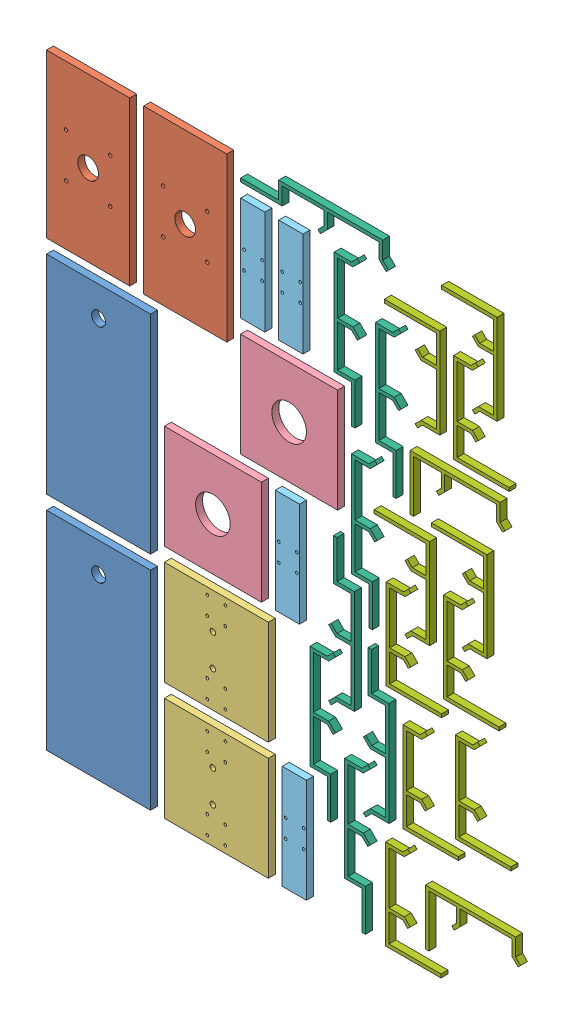
SolidWorks assembly Assem6, configuration Layout1[Steel_10mm_Qnty1]. Lengths in mm.
Overall size (1800 900 10).
32 component instances, 7 part files, 0 mates.
Components (placement in the parent):
- Z_Top_Plate-1: Z_Top_Plate [Default] at (85 160 0) x (1 0 0) z (0 0 -1) size (150 300 10)
- Z_Top_Plate-2: Z_Top_Plate [Default] at (85 480 0) x (1 0 0) z (0 0 -1) size (150 300 10)
- Motor Extension Plate-1: Motor Extension Plate [Default] at (70 767.5 0) x (0 -1 0) z (0 0 -1) size (235 120 10)
- Motor Extension Plate-2: Motor Extension Plate [Default] at (210 767.5 0) x (0 -1 0) z (0 0 -1) size (235 120 10)
- Horizontal_Plate-1: Horizontal_Plate [Default] at (255 85 0) x (0 -1 0) z (1 0 0) size (150 10 150)
- Horizontal_Plate-2: Horizontal_Plate [Default] at (255 255 0) x (0 -1 0) z (1 0 0) size (150 10 150)
- Vertical_Plate-1: Vertical_Plate [Default] at (250 425 0) x (0 -1 0) z (0 0 -1) size (150 140 10)
- Vertical_Plate-2: Vertical_Plate [Default] at (360 595 0) x (0 -1 0) z (0 0 -1) size (150 140 10)
- Lower_Section-1: Lower_Section [Default] at (325 690 0) x (0 0 -1) z (1 0 0) size (10 150 35)
- Lower_Section-2: Lower_Section [Default] at (375 350 0) x (0 0 -1) z (1 0 0) size (10 150 35)
- Lower_Section-3: Lower_Section [Default] at (380 690 0) x (0 0 -1) z (1 0 0) size (10 150 35)
- Lower_Section-4: Lower_Section [Default] at (385 10 0) x (0 0 -1) z (1 0 0) size (10 150 35)
- Drag_Chain_Bracket_Y-1: Drag_Chain_Bracket_Y [Default] at (452.5 873.6352 -10) x (-1 0 0) z (0 0 1) size (213.49 37.02 10)
- Drag_Chain_Bracket_Y-2: Drag_Chain_Bracket_Y [Default] at (406.3648 287.5 -10) x (0 -1 0) z (0 0 1) size (213.49 37.02 10)
- Drag_Chain_Bracket_Y-3: Drag_Chain_Bracket_Y [Default] at (441.3648 797.5 -10) x (0 -1 0) z (0 0 1) size (213.49 37.02 10)
- Drag_Chain_Bracket_Y-4: Drag_Chain_Bracket_Y [Default] at (437.7271 322.9485 -10) x (0 1 0) z (0 0 1) size (213.49 37.02 10)
- Drag_Chain_Bracket_Y-5: Drag_Chain_Bracket_Y [Default] at (456.3648 172.5 -10) x (0 -1 0) z (0 0 1) size (213.49 37.02 10)
- Drag_Chain_Bracket_Y-6: Drag_Chain_Bracket_Y [Default] at (466.3648 557.9485 -10) x (0 -1 0) z (0 0 1) size (213.49 37.02 10)
- Drag_Chain_Bracket_Y-7: Drag_Chain_Bracket_Y [Default] at (487.7271 207.9485 -10) x (0 1 0) z (0 0 1) size (213.49 37.02 10)
- Drag_Chain_Bracket_Y-8: Drag_Chain_Bracket_Y [Default] at (500.8648 739.3204 -10) x (0 -1 0) z (0 0 1) size (213.49 37.02 10)
- Drag_Chain_Bracket-1: Drag_Chain_Bracket [Default] at (532.15 78.5359 -10) x (0 -1 0) z (0 0 1) size (137.07 80 10)
- Drag_Chain_Bracket-2: Drag_Chain_Bracket [Default] at (533.0581 403.9845 -10) x (0 -1 0) z (0 0 1) size (137.07 80 10)
- Drag_Chain_Bracket-3: Drag_Chain_Bracket [Default] at (557.15 237.6785 -10) x (0 -1 0) z (0 0 1) size (137.07 80 10)
- Drag_Chain_Bracket-4: Drag_Chain_Bracket [Default] at (529.6199 478.4641 -10) x (0 1 0) z (0 0 1) size (137.07 80 10)
- Drag_Chain_Bracket-5: Drag_Chain_Bracket [Default] at (544.3224 748.8408 -10) x (0 1 0) z (0 0 1) size (137.07 80 10)
- Drag_Chain_Bracket-6: Drag_Chain_Bracket [Default] at (603.0359 613.9419 -10) x (-1 0 0) z (0 0 1) size (137.07 80 10)
- Drag_Chain_Bracket-7: Drag_Chain_Bracket [Default] at (615.7361 428.9845 -10) x (0 -1 0) z (0 0 1) size (137.07 80 10)
- Drag_Chain_Bracket-8: Drag_Chain_Bracket [Default] at (625.3058 81.9419 -10) x (-1 0 0) z (0 0 1) size (137.07 80 10)
- Drag_Chain_Bracket-9: Drag_Chain_Bracket [Default] at (630.4387 735.5359 -10) x (0 -1 0) z (0 0 1) size (137.07 80 10)
- Drag_Chain_Bracket-10: Drag_Chain_Bracket [Default] at (632.9725 262.6785 -10) x (0 -1 0) z (0 0 1) size (137.07 80 10)
- Drag_Chain_Bracket-11: Drag_Chain_Bracket [Default] at (612.2979 503.4641 -10) x (0 1 0) z (0 0 1) size (137.07 80 10)
- Drag_Chain_Bracket-12: Drag_Chain_Bracket [Default] at (627.0004 807.4987 -10) x (0 1 0) z (0 0 1) size (137.07 80 10)
